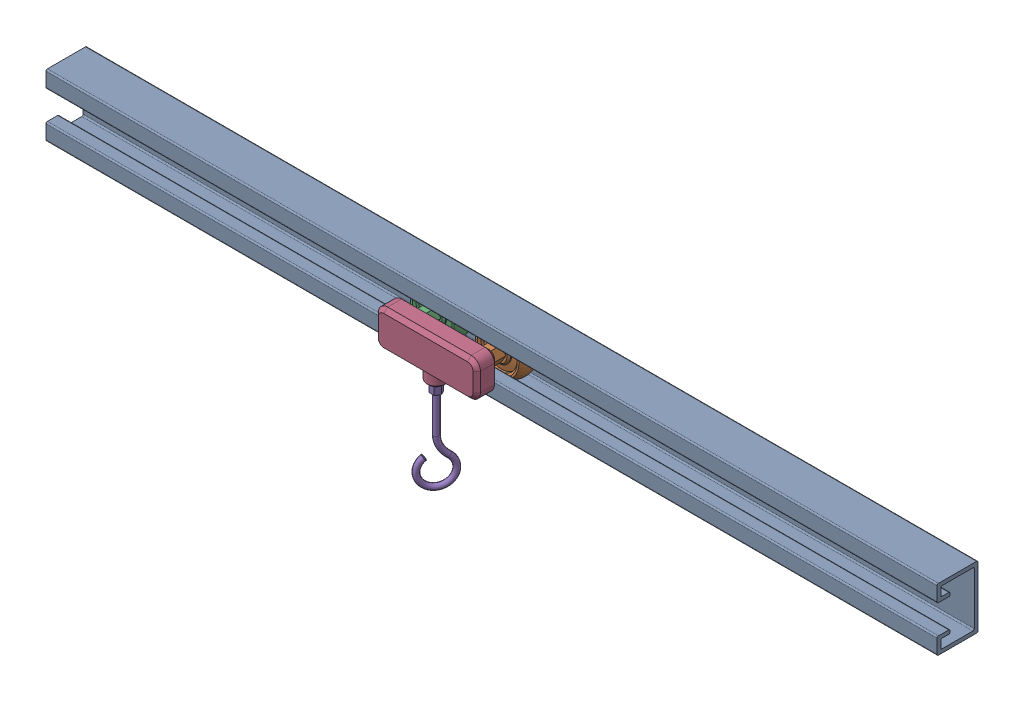
SolidWorks assembly Assem2, configuration Default. Lengths in mm.
Overall size (1219.2 214.71 98.12).
5 component instances, 4 part files, 13 mates.
Components (placement in the parent):
- Bracket-Base-1: Bracket-Base [Default] at origin size (1219.2 85.09 55.88)
- Wheel-1: Wheel [Default] at (596.9 34.925 16.51) size (69.85 69.85 64.77)
- Wheel-2: Wheel [Default] at (508 34.925 16.51) x (-0.5 0.866025 0) z (0 0 1) size (69.85 69.85 64.77)
- Cart-1: Cart [Default] at (552.45 34.925 54.61) size (139.7 63.5 36.83)
- Hook-1: Hook [Default] at (552.45 -15.875 69.215) x (0.848048 0 0.529919) z (-0.529919 0 0.848048) size (12.7 160.65 48.26)
Mates (geometry in assembly coordinates):
- Tangent1: tangent anti-aligned: plane of Bracket-Base-1 through (1219.2 0 0) normal (0 1 0); torus of Wheel-1
- Width1: width aligned: plane of Bracket-Base-1 through (1219.2 0 0) normal (0 0 1); plane of Bracket-Base-1 through (1219.2 62.23 33.02) normal (0 0 -1); plane of Wheel-1 through (596.9 34.925 30.48) normal (0 0 1); plane of Wheel-1 through (596.9 34.925 2.54) normal (0 0 -1)
- Tangent2: tangent anti-aligned: plane of Bracket-Base-1 through (1219.2 0 0) normal (0 1 0); torus of Wheel-2
- Width2: width anti-aligned: plane of Bracket-Base-1 through (1219.2 0 0) normal (0 0 1); plane of Wheel-2 through (1219.2 62.23 33.02) normal (0 0 -1); plane of Bracket-Base-1 through (508 34.925 2.54) normal (0 0 -1); plane of Wheel-2 through (508 34.925 30.48) normal (0 0 1)
- Concentric1: concentric aligned: cylinder of Wheel-2 through (508 34.925 16.51) axis (0 0 -1) radius 5.08; cylinder of Cart-1 through (508 34.925 77.47) axis (0 0 -1) radius 5.715
- Concentric2: concentric aligned: cylinder of Wheel-1 through (596.9 34.925 16.51) axis (0 0 -1) radius 5.08; cylinder of Cart-1 through (596.9 34.925 77.47) axis (0 0 -1) radius 5.715
- Coincident1: coincident anti-aligned: plane of Wheel-2 through (508 34.925 46.99) normal (0 0 1); plane of Cart-1 through (508 34.925 46.99) normal (0 0 -1)
- Parallel1: parallel anti-aligned: plane of Bracket-Base-1 through (1219.2 57.15 45.72) normal (0 -1 0); plane of Wheel-2 through (513.8659 45.085 -14.4213) normal (0 1 0)
- Parallel2: parallel anti-aligned: plane of Bracket-Base-1 through (1219.2 57.15 45.72) normal (0 -1 0); plane of Wheel-1 through (602.7659 45.085 -14.4213) normal (0 1 0)
- Distance2: distance = 482.6 mm aligned: plane of Bracket-Base-1 through (0 0 0) normal (-1 0 0); plane of Cart-1 through (482.6 34.925 77.47) normal (-1 0 0)
- Concentric3: concentric aligned: cylinder of Cart-1 through (552.45 22.225 69.215) axis (0 -1 0) radius 5.08; cylinder of Hook-1 through (552.45 74.6934 69.215) axis (0 -1 0) radius 5.08
- Coincident2: coincident anti-aligned: plane of Cart-1 through (552.45 -3.175 69.215) normal (0 -1 0); plane of Hook-1 through (552.45 -3.175 69.215) normal (0 1 0)
- Angle1: planar angle = 1.012291 rad aligned: line of Hook-1 through (555.8923 -15.875 75.6891) axis (0.529919 0 -0.848048); line of Cart-1 through (495.3 14.605 83.82) axis (1 0 0)
